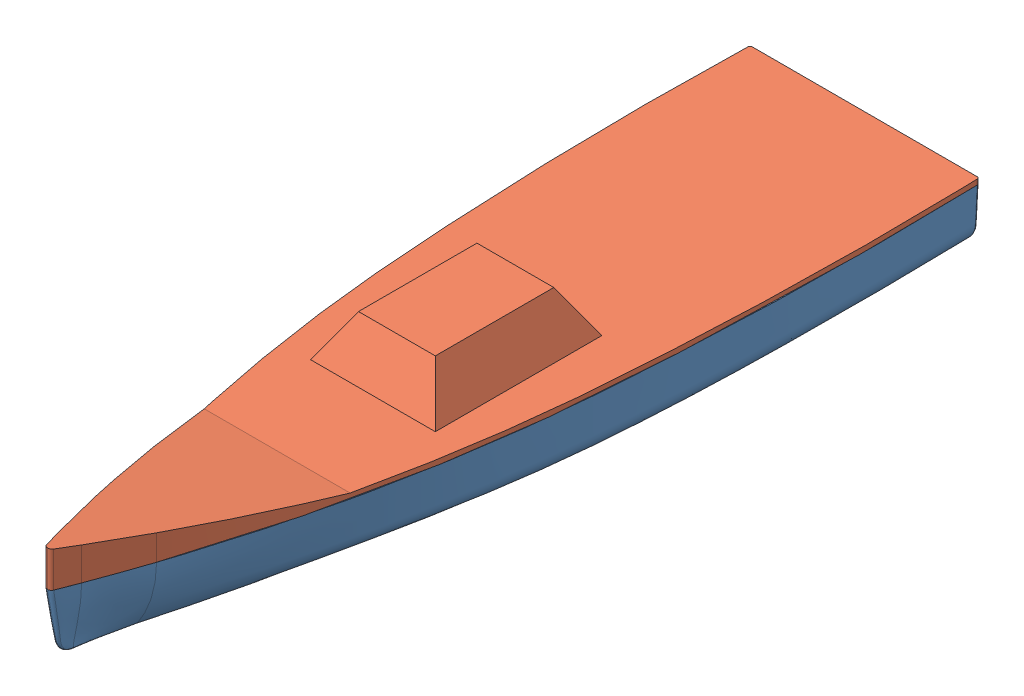
SolidWorks assembly Hull & Deck, configuration Default. Lengths in mm.
Overall size (590.36 317.51 2005.15).
2 component instances, 2 part files, 3 mates.
Components (placement in the parent):
- Hull 9.2 rounder bow-1: Hull 9.2 rounder bow [JustSolid] at origin size (590.36 218.85 2004.6)
- Deck-1: Deck [Default] at (-7.7182 0 648.2956) size (572.24 114.31 1994.46)
Mates (geometry in assembly coordinates):
- Coincident2: coincident aligned: plane of Hull 9.2 rounder bow-1 through (0 0 0) normal (0 0 -1); plane of Deck-1 through (274.4604 12.7 0) normal (0 0 -1)
- Coincident3: coincident aligned: plane of Deck-1 through (0 0 648.2956) normal (1 0 0); plane of assembly through (0 0 0) normal (1 0 0)
- Coincident4: coincident anti-aligned: plane of Hull 9.2 rounder bow-1 through (279.4 0 0) normal (0 1 0); plane of Deck-1 through (5.3677 0 1992.242) normal (0 -1 0)
